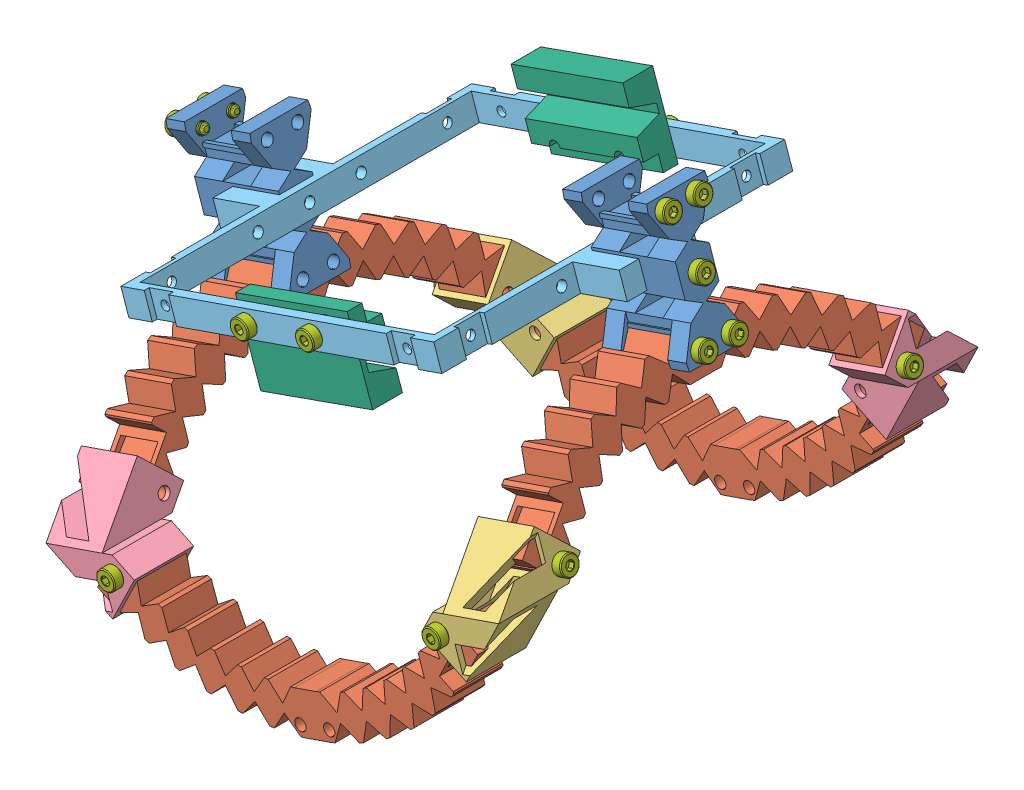
SolidWorks assembly SMS-unit1, configuration Default. Lengths in mm.
Overall size (121.01 106.79 101.13).
35 component instances, 7 part files, 78 mates.
Components (placement in the parent):
- center connector-3: center connector [Default] at (-86.1995 55.0557 -4.4744) x (0 0 -1) z (-0.326892 0.945062 0) size (12.09 18 26.59)
- center connector-4: center connector [Default] at (-5.9085 82.8279 -4.4744) x (0 0 -1) z (-0.326892 0.945062 0) size (12.09 18 26.59)
- bending structure-7: bending structure [Default] at (-38.7902 -51.4159 -4.4744) x (0 0 1) z (0.326892 -0.945062 0) size (81.4 10 56.11)
- bending structure-8: bending structure [Default] at (41.5008 -23.6437 -4.4744) x (0 0 1) z (0.326892 -0.945062 0) size (81.4 10 56.11)
- bend connector_type1-3: bend connector_type1 [Default] at (-39.8238 -45.3687 -21.1339) x (-0.326892 0.945062 0) z (-0.945062 -0.326892 0) size (21.21 17.68 17.68)
- bend connector_type2-3: bend connector_type2 [Default] at (-46.7582 -25.3209 36.9337) x (0 0 1) z (-0.945062 -0.326892 0) size (17.68 21.21 17.68)
- bend connector_type1-4: bend connector_type1 [Default] at (-3.4733 12.0974 32.0048) x (0.326892 -0.945062 0) z (0 0 1) size (21.21 17.68 17.68)
- bend connector_type2-4: bend connector_type2 [Default] at (22.1921 -1.4714 -45.8826) x (0 0 -1) z (0.945062 0.326892 0) size (17.68 21.21 17.68)
- bending structure-9: bending structure [Default] at (-21.1961 12.3719 43.0048) x (0.945062 0.326892 0) z (-0.326892 0.945062 0) size (81.4 10 56.11)
- bending structure-10: bending structure [Default] at (-21.1961 12.3719 -41.9537) x (0.945062 0.326892 0) z (-0.326892 0.945062 0) size (81.4 10 56.11)
- mocap connector_end-2: mocap connector_end [Default] at (-22.636 16.5983 -4.4744) x (0 0 -1) z (0.945062 0.326892 0) size (71 5 87)
- ring connect_type2_2-4: ring connect_type2_2 [Default] at (-10.3832 17.9892 23.0256) x (0 0 1) z (0.333057 -0.942907 0) size (7.03 24 15.53)
- ring connect_type2_2-5: ring connect_type2_2 [Default] at (-13.9236 28.0123 -31.9744) x (0 0 -1) z (-0.333057 0.942907 0) size (7.03 24 15.53)
- M2  SCREW-23: M2  SCREW [Default] at (-71.0046 14.1857 -1.3878) x (0 0 -1) z (0.945062 0.326892 0) size (3.8 3.8 7.09)
- M2  SCREW-24: M2  SCREW [Default] at (-71.0046 14.1857 -7.5611) x (0 0 -1) z (0.945062 0.326892 0) size (3.8 3.8 7.09)
- M2  SCREW-29: M2  SCREW [Default] at (16.8469 44.5731 -7.5611) x (0 0 1) z (-0.945062 -0.326892 0) size (3.8 3.8 7.09)
- M2  SCREW-30: M2  SCREW [Default] at (16.8469 44.5731 -1.3878) x (0 0 1) z (-0.945062 -0.326892 0) size (3.8 3.8 7.09)
- M2  SCREW-31: M2  SCREW [Default] at (-67.3986 3.7605 -4.4744) x (-0.166258 0.480661 -0.861001) z (0.945062 0.326892 0) size (3.8 3.8 7.09)
- M2  SCREW-32: M2  SCREW [Default] at (-63.7926 -6.6648 -1.3878) x (-0.174265 0.50381 -0.846054) z (0.945062 0.326892 0) size (3.8 3.8 7.09)
- M2  SCREW-33: M2  SCREW [Default] at (-63.7926 -6.6648 -7.5611) x (-0.159083 0.459918 -0.873595) z (0.945062 0.326892 0) size (3.8 3.8 7.09)
- M2  SCREW-34: M2  SCREW [Default] at (20.4529 34.1478 -4.4744) x (0 0 1) z (-0.945062 -0.326892 0) size (3.8 3.8 7.09)
- M2  SCREW-35: M2  SCREW [Default] at (24.0589 23.7226 -1.3878) x (0.119998 -0.346921 0.930186) z (-0.945062 -0.326892 0) size (3.8 3.8 7.09)
- M2  SCREW-36: M2  SCREW [Default] at (24.0589 23.7226 -7.5611) x (0.200383 -0.579319 0.790086) z (-0.945062 -0.326892 0) size (3.8 3.8 7.09)
- M2  SCREW-37: M2  SCREW [Default] at (-16.868 21.3355 -34.9744) size (3.8 3.8 7.09)
- M2  SCREW-38: M2  SCREW [Default] at (-30.0687 16.6727 -34.9744) size (3.8 3.8 7.09)
- M2  SCREW-39: M2  SCREW [Default] at (-16.868 21.3355 26.0256) x (-0.838299 0.545211 0) z (0 0 -1) size (3.8 3.8 7.09)
- M2  SCREW-40: M2  SCREW [Default] at (-30.0687 16.6727 26.0256) x (-0.777064 0.629422 0) z (0 0 -1) size (3.8 3.8 7.09)
- M2  SCREW-41: M2  SCREW [Default] at (-54.46 -24.4684 -39.3065) x (-0.045968 0.132894 -0.990064) z (0.945062 0.326892 0) size (3.8 3.8 7.09)
- M2  SCREW-42: M2  SCREW [Default] at (-54.46 -24.4684 30.3576) x (0 0 -1) z (0.945062 0.326892 0) size (3.8 3.8 7.09)
- M2  SCREW-43: M2  SCREW [Default] at (27.7211 3.9577 -39.3065) x (0.200383 -0.579319 0.790086) z (-0.945062 -0.326892 0) size (3.8 3.8 7.09)
- M2  SCREW-44: M2  SCREW [Default] at (27.7211 3.9577 30.3576) x (0.186457 -0.539058 0.821371) z (-0.945062 -0.326892 0) size (3.8 3.8 7.09)
- M2  SCREW-45: M2  SCREW [Default] at (-44.1151 -27.9233 39.0048) x (-0.703452 -0.710742 0) z (0 0 -1) size (3.8 3.8 7.09)
- M2  SCREW-46: M2  SCREW [Default] at (21.7218 -5.1507 39.0048) x (-0.691524 -0.722354 0) z (0 0 -1) size (3.8 3.8 7.09)
- M2  SCREW-47: M2  SCREW [Default] at (21.7218 -5.1507 -47.9537) x (0.986731 -0.162364 0) z (0 0 1) size (3.8 3.8 7.09)
- M2  SCREW-48: M2  SCREW [Default] at (-44.1151 -27.9233 -47.9537) x (0.889704 0.456538 0) z (0 0 1) size (3.8 3.8 7.09)
Mates (geometry in assembly coordinates):
- Coincident36: coincident anti-aligned: plane of center connector-3 through (-48.2408 -54.6848 -4.4744) normal (0.945062 0.326892 0); plane of bending structure-7 through (-48.2408 -54.6848 -4.4744) normal (-0.945062 -0.326892 0)
- Concentric28: concentric anti-aligned: cylinder of center connector-3 through (-65.6827 -7.3185 -1.3878) axis (0.945062 0.326892 0) radius 1.15; cylinder of bending structure-7 through (-45.8364 -0.4538 -1.3878) axis (-0.945062 -0.326892 0) radius 1.15
- Concentric29: concentric anti-aligned: cylinder of center connector-3 through (-65.6827 -7.3185 -7.5611) axis (0.945062 0.326892 0) radius 1.15; cylinder of bending structure-7 through (-45.8364 -0.4538 -7.5611) axis (-0.945062 -0.326892 0) radius 1.15
- Coincident37: coincident anti-aligned: plane of center connector-4 through (41.5008 -23.6437 -4.4744) normal (-0.945062 -0.326892 0); plane of bending structure-8 through (41.5008 -23.6437 -4.4744) normal (0.945062 0.326892 0)
- Concentric30: concentric aligned: cylinder of center connector-4 through (25.949 24.3764 -1.3878) axis (-0.945062 -0.326892 0) radius 1.15; cylinder of bending structure-8 through (34.4546 27.3184 -1.3878) axis (-0.945062 -0.326892 0) radius 1.15
- Concentric31: concentric aligned: cylinder of center connector-4 through (25.949 24.3764 -7.5611) axis (-0.945062 -0.326892 0) radius 1.15; cylinder of bending structure-8 through (34.4546 27.3184 -7.5611) axis (-0.945062 -0.326892 0) radius 1.15
- Coincident40: coincident anti-aligned: plane of bending structure-7 through (-37.6345 -54.7572 -8.01) normal (0.231148 -0.66826 -0.707107); plane of bend connector_type1-3 through (-47.9139 -21.9796 -42.3471) normal (-0.231148 0.66826 0.707107)
- Coincident41: coincident anti-aligned: plane of bending structure-7 through (-59.2342 -22.9024 -45.1755) normal (-0.231148 0.66826 -0.707107); plane of bend connector_type1-3 through (-49.7836 -19.6335 -45.1755) normal (0.231148 -0.66826 0.707107)
- Coincident42: coincident anti-aligned: plane of bending structure-7 through (-38.7902 -51.4159 -4.4744) normal (0.945062 0.326892 0); plane of bend connector_type1-3 through (-49.7836 -19.6335 -45.1755) normal (-0.945062 -0.326892 0)
- Coincident43: coincident anti-aligned: plane of bending structure-7 through (-38.7902 -51.4159 -4.4744) normal (0.945062 0.326892 0); plane of bend connector_type2-3 through (-49.7836 -19.6335 36.2266) normal (-0.945062 -0.326892 0)
- Coincident44: coincident anti-aligned: plane of bending structure-7 through (-37.6345 -54.7572 -0.9389) normal (0.231148 -0.66826 0.707107); plane of bend connector_type2-3 through (-47.9139 -21.9796 33.3982) normal (-0.231148 0.66826 -0.707107)
- Coincident45: coincident anti-aligned: plane of bending structure-7 through (-57.385 -28.2485 30.5698) normal (0.231148 -0.66826 -0.707107); plane of bend connector_type2-3 through (-47.9344 -24.9796 30.5698) normal (-0.231148 0.66826 0.707107)
- Coincident46: coincident anti-aligned: plane of bending structure-8 through (42.6566 -26.985 -8.01) normal (0.231148 -0.66826 -0.707107); plane of bend connector_type2-4 through (21.0364 1.8699 -42.3471) normal (-0.231148 0.66826 0.707107)
- Coincident47: coincident anti-aligned: plane of bending structure-8 through (32.0502 -26.9126 -4.4744) normal (-0.945062 -0.326892 0); plane of bend connector_type2-4 through (21.0568 4.8698 -45.1755) normal (0.945062 0.326892 0)
- Coincident48: coincident anti-aligned: plane of bending structure-8 through (21.0568 4.8698 -45.1755) normal (-0.231148 0.66826 -0.707107); plane of bend connector_type2-4 through (21.0568 4.8698 -45.1755) normal (0.231148 -0.66826 0.707107)
- Coincident49: coincident anti-aligned: plane of bending structure-8 through (42.6566 -26.985 -0.9389) normal (0.231148 -0.66826 0.707107); plane of bend connector_type1-4 through (26.5001 1.152 30.9337) normal (-0.231148 0.66826 -0.707107)
- Coincident50: coincident anti-aligned: plane of bending structure-8 through (42.6566 -26.985 -0.9389) normal (0.231148 -0.66826 0.707107); plane of bend connector_type1-4 through (26.5001 1.152 30.9337) normal (-0.231148 0.66826 -0.707107)
- Coincident51: coincident anti-aligned: plane of bending structure-8 through (21.0568 4.8698 36.2266) normal (-0.231148 0.66826 0.707107); plane of bend connector_type1-4 through (21.0568 4.8698 36.2266) normal (0.231148 -0.66826 -0.707107)
- Coincident52: coincident anti-aligned: plane of bending structure-8 through (32.0502 -26.9126 -4.4744) normal (-0.945062 -0.326892 0); plane of bend connector_type1-4 through (21.0568 4.8698 36.2266) normal (0.945062 0.326892 0)
- Coincident55: coincident anti-aligned: plane of bend connector_type1-4 through (28.2623 -6.1057 43.0048) normal (0 0 -1); plane of bending structure-9 through (-21.1961 12.3719 43.0048) normal (0 0 1)
- Concentric32: concentric anti-aligned: cylinder of bend connector_type1-4 through (21.7218 -5.1507 18.0048) axis (0 0 1) radius 1.15; cylinder of bending structure-9 through (21.7218 -5.1507 59.0048) axis (0 0 -1) radius 1.15
- Concentric33: concentric anti-aligned: cylinder of bend connector_type2-3 through (-44.1151 -27.9233 18.0048) axis (0 0 1) radius 1.15; cylinder of bending structure-9 through (-44.1151 -27.9233 59.0048) axis (0 0 -1) radius 1.15
- Coincident56: coincident anti-aligned: plane of bend connector_type2-4 through (28.2623 -6.1057 -51.9537) normal (0 0 1); plane of bending structure-10 through (-21.1961 12.3719 -51.9537) normal (0 0 -1)
- Concentric34: concentric aligned: cylinder of bend connector_type1-3 through (-44.1151 -27.9233 -26.9537) axis (0 0 -1) radius 1.15; cylinder of bending structure-10 through (-44.1151 -27.9233 -25.9537) axis (0 0 -1) radius 1.15
- Concentric35: concentric aligned: cylinder of bend connector_type2-4 through (21.7218 -5.1507 -26.9537) axis (0 0 -1) radius 1.15; cylinder of bending structure-10 through (21.7218 -5.1507 -25.9537) axis (0 0 -1) radius 1.15
- Coincident58: coincident anti-aligned: plane of center connector-3 through (-72.9686 59.6322 -4.4744) normal (0.945062 0.326892 0); plane of mocap connector_end-2 through (-55.93 10.3727 31.0256) normal (-0.945062 -0.326892 0)
- Concentric38: concentric anti-aligned: cylinder of center connector-4 through (29.9035 37.4168 -4.4744) axis (-0.945062 -0.326892 0) radius 1.15; cylinder of mocap connector_end-2 through (-76.8492 0.4915 -4.4744) axis (0.945062 0.326892 0) radius 1
- Coincident59: coincident anti-aligned: plane of mocap connector_end-2 through (-54.0399 11.0265 29.0256) normal (0 0 -1); plane of ring connect_type2_2-4 through (-16.868 21.3355 29.0256) normal (0 0 1)
- Concentric39: concentric anti-aligned: circle of mocap connector-2; circle of ring connect_type2_2-4
- Concentric40: concentric aligned: cylinder of mocap connector_end-2 through (-30.0687 16.6727 81.0256) axis (0 0 -1) radius 0.9; cylinder of ring connect_type2_2-4 through (-30.0687 16.6727 29.0256) axis (0 0 -1) radius 0.9
- Coincident61: coincident anti-aligned: plane of mocap connector_end-2 through (-54.0399 11.0265 -37.9744) normal (0 0 1); plane of ring connect_type2_2-5 through (-30.0687 16.6727 -37.9744) normal (0 0 -1)
- Concentric41: concentric anti-aligned: cylinder of mocap connector_end-2 through (-30.0687 16.6727 81.0256) axis (0 0 -1) radius 0.9; cylinder of ring connect_type2_2-5 through (-30.0687 16.6727 -37.9744) axis (0 0 1) radius 0.9
- Concentric42: concentric anti-aligned: cylinder of mocap connector_end-2 through (-16.868 21.3355 81.0256) axis (0 0 -1) radius 0.9; cylinder of ring connect_type2_2-5 through (-16.868 21.3355 -37.9744) axis (0 0 1) radius 0.9
- Coincident109: coincident anti-aligned: plane of center connector-3 through (-89.9797 53.7481 -4.4744) normal (-0.945062 -0.326892 0); plane of M2  SCREW-24 through (-75.7299 12.5512 -7.5611) normal (0.945062 0.326892 0)
- Concentric67: concentric aligned: cylinder of center connector-3 through (-72.8948 13.5319 -7.5611) axis (0.945062 0.326892 0) radius 1.15; cylinder of M2  SCREW-24 through (-77.6201 11.8974 -7.5611) axis (0.945062 0.326892 0) radius 1.9
- Coincident110: coincident anti-aligned: plane of center connector-3 through (-89.9797 53.7481 -4.4744) normal (-0.945062 -0.326892 0); plane of M2  SCREW-23 through (-75.7299 12.5512 -1.3878) normal (0.945062 0.326892 0)
- Concentric68: concentric aligned: cylinder of center connector-3 through (-72.8948 13.5319 -1.3878) axis (0.945062 0.326892 0) radius 1.15; cylinder of M2  SCREW-23 through (-77.6201 11.8974 -1.3878) axis (0.945062 0.326892 0) radius 1.9
- Coincident115: coincident anti-aligned: plane of center connector-4 through (7.3224 87.4044 -4.4744) normal (0.945062 0.326892 0); plane of M2  SCREW-30 through (21.5722 46.2075 -1.3878) normal (-0.945062 -0.326892 0)
- Concentric73: concentric aligned: cylinder of center connector-4 through (18.737 45.2268 -1.3878) axis (-0.945062 -0.326892 0) radius 1.15; cylinder of M2  SCREW-30 through (23.4623 46.8613 -1.3878) axis (-0.945062 -0.326892 0) radius 1.9
- Coincident116: coincident anti-aligned: plane of center connector-4 through (7.3224 87.4044 -4.4744) normal (0.945062 0.326892 0); plane of M2  SCREW-29 through (21.5722 46.2075 -7.5611) normal (-0.945062 -0.326892 0)
- Concentric74: concentric aligned: cylinder of center connector-4 through (18.737 45.2268 -7.5611) axis (-0.945062 -0.326892 0) radius 1.15; cylinder of M2  SCREW-29 through (23.4623 46.8613 -7.5611) axis (-0.945062 -0.326892 0) radius 1.9
- Coincident117: coincident anti-aligned: plane of center connector-3 through (-89.9797 53.7481 -4.4744) normal (-0.945062 -0.326892 0); plane of M2  SCREW-31 through (-72.1239 2.126 -4.4744) normal (0.945062 0.326892 0)
- Concentric75: concentric anti-aligned: cylinder of center connector-3 through (-50.3875 9.6445 -4.4744) axis (-0.945062 -0.326892 0) radius 1.15; cylinder of M2  SCREW-31 through (-74.014 1.4722 -4.4744) axis (0.945062 0.326892 0) radius 1.9
- Coincident118: coincident anti-aligned: plane of center connector-3 through (-89.9797 53.7481 -4.4744) normal (-0.945062 -0.326892 0); plane of M2  SCREW-33 through (-68.5179 -8.2992 -7.5611) normal (0.945062 0.326892 0)
- Concentric76: concentric aligned: cylinder of center connector-3 through (-65.6827 -7.3185 -7.5611) axis (0.945062 0.326892 0) radius 1.15; cylinder of M2  SCREW-33 through (-70.408 -8.953 -7.5611) axis (0.945062 0.326892 0) radius 1.9
- Coincident119: coincident anti-aligned: plane of center connector-3 through (-89.9797 53.7481 -4.4744) normal (-0.945062 -0.326892 0); plane of M2  SCREW-32 through (-68.5179 -8.2992 -1.3878) normal (0.945062 0.326892 0)
- Concentric77: concentric aligned: cylinder of center connector-3 through (-65.6827 -7.3185 -1.3878) axis (0.945062 0.326892 0) radius 1.15; cylinder of M2  SCREW-32 through (-70.408 -8.953 -1.3878) axis (0.945062 0.326892 0) radius 1.9
- Coincident120: coincident anti-aligned: plane of center connector-4 through (7.3224 87.4044 -4.4744) normal (0.945062 0.326892 0); plane of M2  SCREW-34 through (25.1782 35.7823 -4.4744) normal (-0.945062 -0.326892 0)
- Concentric78: concentric aligned: cylinder of center connector-4 through (29.9035 37.4168 -4.4744) axis (-0.945062 -0.326892 0) radius 1.15; circle of M2  SCREW-34
- Coincident121: coincident anti-aligned: plane of center connector-4 through (7.3224 87.4044 -4.4744) normal (0.945062 0.326892 0); plane of M2  SCREW-35 through (28.7842 25.3571 -1.3878) normal (-0.945062 -0.326892 0)
- Coincident122: coincident anti-aligned: plane of center connector-4 through (7.3224 87.4044 -4.4744) normal (0.945062 0.326892 0); plane of M2  SCREW-36 through (28.7842 25.3571 -7.5611) normal (-0.945062 -0.326892 0)
- Concentric79: concentric aligned: cylinder of center connector-4 through (25.949 24.3764 -1.3878) axis (-0.945062 -0.326892 0) radius 1.15; cylinder of M2  SCREW-35 through (30.6744 26.0109 -1.3878) axis (-0.945062 -0.326892 0) radius 1.9
- Concentric80: concentric aligned: cylinder of center connector-4 through (25.949 24.3764 -7.5611) axis (-0.945062 -0.326892 0) radius 1.15; cylinder of M2  SCREW-36 through (30.6744 26.0109 -7.5611) axis (-0.945062 -0.326892 0) radius 1.9
- Coincident123: coincident anti-aligned: plane of mocap connector_end-2 through (-55.93 10.3727 -39.9744) normal (0 0 -1); plane of M2  SCREW-37 through (-16.868 21.3355 -39.9744) normal (0 0 1)
- Coincident124: coincident anti-aligned: plane of mocap connector_end-2 through (-55.93 10.3727 -39.9744) normal (0 0 -1); plane of M2  SCREW-38 through (-30.0687 16.6727 -39.9744) normal (0 0 1)
- Concentric81: concentric anti-aligned: cylinder of mocap connector_end-2 through (-30.0687 16.6727 81.0256) axis (0 0 -1) radius 0.9; cylinder of M2  SCREW-38 through (-30.0687 16.6727 -41.9744) axis (0 0 1) radius 1.9
- Concentric82: concentric anti-aligned: cylinder of mocap connector_end-2 through (-16.868 21.3355 81.0256) axis (0 0 -1) radius 0.9; circle of M2  SCREW-37
- Coincident126: coincident anti-aligned: plane of mocap connector_end-2 through (-55.93 10.3727 31.0256) normal (0 0 1); plane of M2  SCREW-40 through (-30.0687 16.6727 31.0256) normal (0 0 -1)
- Concentric83: concentric aligned: cylinder of mocap connector_end-2 through (-30.0687 16.6727 81.0256) axis (0 0 -1) radius 0.9; cylinder of M2  SCREW-40 through (-30.0687 16.6727 33.0256) axis (0 0 -1) radius 1.9
- Coincident127: coincident anti-aligned: plane of mocap connector_end-2 through (-55.93 10.3727 31.0256) normal (0 0 1); plane of M2  SCREW-39 through (-16.868 21.3355 31.0256) normal (0 0 -1)
- Concentric84: concentric aligned: cylinder of mocap connector_end-2 through (-16.868 21.3355 81.0256) axis (0 0 -1) radius 0.9; cylinder of M2  SCREW-39 through (-16.868 21.3355 33.0256) axis (0 0 -1) radius 1.9
- Coincident128: coincident anti-aligned: plane of bend connector_type2-3 through (-58.0989 -29.2437 36.9337) normal (-0.945062 -0.326892 0); plane of M2  SCREW-42 through (-59.1853 -26.1028 30.3576) normal (0.945062 0.326892 0)
- Concentric85: concentric anti-aligned: cylinder of bend connector_type2-3 through (-34.6137 -17.6036 30.3576) axis (-0.945062 -0.326892 0) radius 1.15; cylinder of M2  SCREW-42 through (-61.0754 -26.7566 30.3576) axis (0.945062 0.326892 0) radius 1.9
- Coincident129: coincident anti-aligned: plane of bend connector_type1-3 through (-58.0989 -29.2437 -45.8826) normal (-0.945062 -0.326892 0); plane of M2  SCREW-41 through (-59.1853 -26.1028 -39.3065) normal (0.945062 0.326892 0)
- Concentric86: concentric anti-aligned: cylinder of bend connector_type1-3 through (-34.6137 -17.6036 -39.3065) axis (-0.945062 -0.326892 0) radius 1.15; circle of M2  SCREW-41
- Coincident130: coincident anti-aligned: plane of bend connector_type2-4 through (33.5328 2.4513 -45.8826) normal (0.945062 0.326892 0); plane of M2  SCREW-43 through (32.4464 5.5921 -39.3065) normal (-0.945062 -0.326892 0)
- Concentric87: concentric anti-aligned: cylinder of bend connector_type2-4 through (7.8748 -2.9071 -39.3065) axis (0.945062 0.326892 0) radius 1.15; cylinder of M2  SCREW-43 through (34.3366 6.2459 -39.3065) axis (-0.945062 -0.326892 0) radius 1.9
- Coincident131: coincident anti-aligned: plane of bend connector_type1-4 through (33.5328 2.4513 32.0048) normal (0.945062 0.326892 0); plane of M2  SCREW-44 through (32.4464 5.5921 30.3576) normal (-0.945062 -0.326892 0)
- Concentric88: concentric anti-aligned: cylinder of bend connector_type1-4 through (7.8748 -2.9071 30.3576) axis (0.945062 0.326892 0) radius 1.15; cylinder of M2  SCREW-44 through (34.3366 6.2459 30.3576) axis (-0.945062 -0.326892 0) radius 1.9
- Coincident133: coincident anti-aligned: plane of bend connector_type2-3 through (-46.7582 -25.3209 44.0048) normal (0 0 1); plane of M2  SCREW-45 through (-44.1151 -27.9233 44.0048) normal (0 0 -1)
- Concentric89: concentric anti-aligned: cylinder of bend connector_type2-3 through (-44.1151 -27.9233 18.0048) axis (0 0 1) radius 1.15; cylinder of M2  SCREW-45 through (-44.1151 -27.9233 46.0048) axis (0 0 -1) radius 1.9
- Concentric90: concentric aligned: cylinder of mocap connector_end-2 through (-76.8492 0.4915 -4.4744) axis (0.945062 0.326892 0) radius 1; cylinder of M2  SCREW-31 through (-74.014 1.4722 -4.4744) axis (0.945062 0.326892 0) radius 1.9
- Coincident134: coincident anti-aligned: plane of bend connector_type1-4 through (26.8502 0.1398 44.0048) normal (0 0 1); plane of M2  SCREW-46 through (21.7218 -5.1507 44.0048) normal (0 0 -1)
- Concentric91: concentric anti-aligned: cylinder of bend connector_type1-4 through (21.7218 -5.1507 18.0048) axis (0 0 1) radius 1.15; cylinder of M2  SCREW-46 through (21.7218 -5.1507 46.0048) axis (0 0 -1) radius 1.9
- Coincident135: coincident anti-aligned: plane of bend connector_type2-4 through (22.1921 -1.4714 -52.9537) normal (0 0 -1); plane of M2  SCREW-47 through (21.7218 -5.1507 -52.9537) normal (0 0 1)
- Concentric92: concentric anti-aligned: cylinder of bend connector_type2-4 through (21.7218 -5.1507 -26.9537) axis (0 0 -1) radius 1.15; cylinder of M2  SCREW-47 through (21.7218 -5.1507 -54.9537) axis (0 0 1) radius 1.9
- Coincident136: coincident anti-aligned: plane of bend connector_type1-3 through (-46.7582 -25.3209 -52.9537) normal (0 0 -1); plane of M2  SCREW-48 through (-44.1151 -27.9233 -52.9537) normal (0 0 1)
- Concentric93: concentric anti-aligned: circle of bending structure-10; cylinder of M2  SCREW-48 through (-44.1151 -27.9233 -54.9537) axis (0 0 1) radius 1.9
